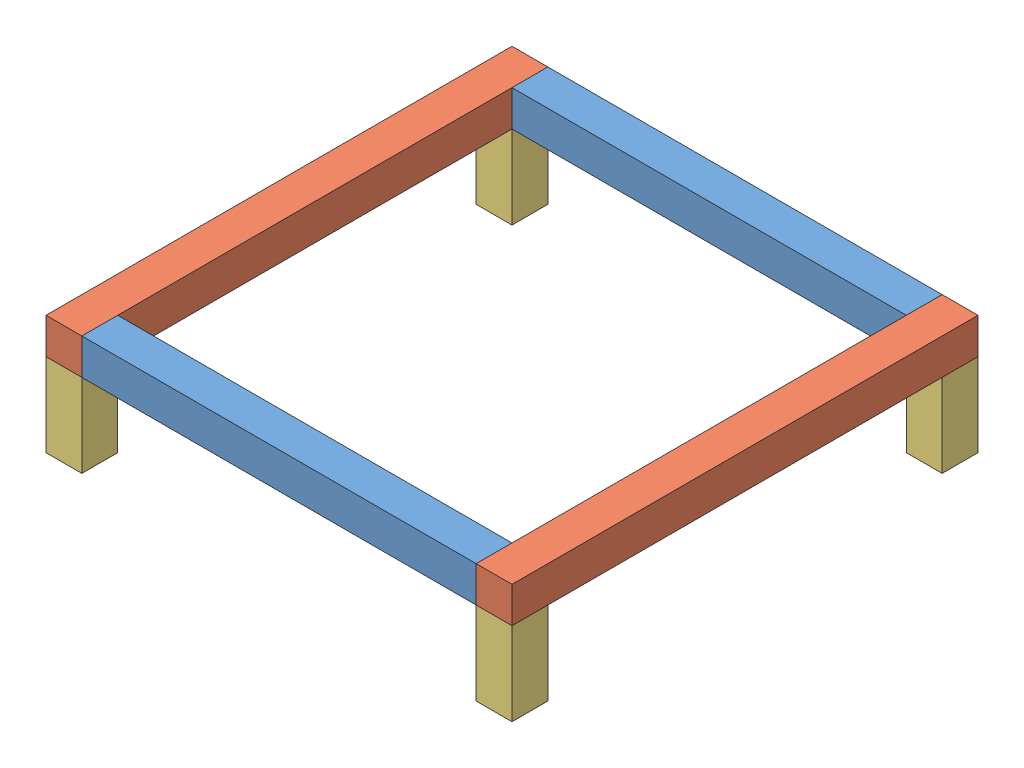
SolidWorks assembly MechanismHolder, configuration Default. Lengths in mm.
Overall size (330.2 84.33 330.2).
8 component instances, 3 part files, 21 mates.
Components (placement in the parent):
- 9.5in-1: 9.5in [Default] at (108.737 108.4161 187.2628) size (279.4 25.4 25.4)
- 11.5in-1: 11.5in [Default] at (261.137 108.4161 339.6628) x (0 0 1) z (-1 0 0) size (330.2 25.4 25.4)
- 9.5in-2: 9.5in [Default] at (108.737 108.4161 492.0628) size (279.4 25.4 25.4)
- 11.5in-2: 11.5in [Default] at (-43.663 108.4161 339.6628) x (0 0 -1) z (1 0 0) size (330.2 25.4 25.4)
- 2.32in-1: 2.32in [Default] at (-43.663 49.4881 492.0628) size (25.4 58.93 25.4)
- 2.32in-2: 2.32in [Default] at (-43.663 49.4881 187.2628) size (25.4 58.93 25.4)
- 2.32in-3: 2.32in [Default] at (261.137 49.4881 187.2628) size (25.4 58.93 25.4)
- 2.32in-4: 2.32in [Default] at (261.137 49.4881 492.0628) size (25.4 58.93 25.4)
Mates (geometry in assembly coordinates):
- Coincident1: coincident aligned: plane of 9.5in-2 through (108.737 133.8161 492.0628) normal (0 1 0); plane of 11.5in-2 through (-43.663 133.8161 339.6628) normal (0 1 0)
- Coincident2: coincident aligned: plane of 9.5in-1 through (108.737 133.8161 187.2628) normal (0 1 0); plane of 11.5in-2 through (-43.663 133.8161 339.6628) normal (0 1 0)
- Coincident3: coincident aligned: plane of 9.5in-1 through (108.737 133.8161 187.2628) normal (0 1 0); plane of 11.5in-1 through (261.137 133.8161 339.6628) normal (0 1 0)
- Coincident4: coincident anti-aligned: plane of 9.5in-2 through (-30.963 133.8161 504.7628) normal (-1 0 0); plane of 11.5in-2 through (-30.963 133.8161 504.7628) normal (1 0 0)
- Coincident5: coincident: plane of 9.5in-2 through (-30.963 133.8161 504.7628) normal (0 0 1); line of 11.5in-2 through (-56.363 133.8161 504.7628) axis (1 0 0)
- Coincident6: coincident anti-aligned: plane of 9.5in-1 through (-30.963 133.8161 199.9628) normal (-1 0 0); plane of 11.5in-2 through (-30.963 133.8161 504.7628) normal (1 0 0)
- Coincident7: coincident aligned: plane of 9.5in-1 through (-30.963 133.8161 174.5628) normal (0 0 -1); plane of 11.5in-2 through (-30.963 133.8161 174.5628) normal (0 0 -1)
- Coincident8: coincident aligned: plane of 9.5in-1 through (-30.963 133.8161 174.5628) normal (0 0 -1); plane of 11.5in-1 through (248.437 133.8161 174.5628) normal (0 0 -1)
- Coincident9: coincident anti-aligned: plane of 11.5in-1 through (248.437 133.8161 174.5628) normal (-1 0 0); plane of 9.5in-2 through (248.437 133.8161 504.7628) normal (1 0 0)
- Coincident10: coincident: plane of 9.5in-1 through (108.737 108.4161 187.2628) normal (0 -1 0); plane of 2.32in-2 through (-43.663 108.4161 200.1959) normal (0 1 0)
- Coincident11: coincident: plane of 9.5in-2 through (108.737 108.4161 492.0628) normal (0 -1 0); plane of 2.32in-3 through (235.737 142.1752 203.3999) normal (0 1 0)
- Coincident12: coincident: plane of 11.5in-1 through (261.137 108.4161 339.6628) normal (0 -1 0); plane of 2.32in-4 through (303.7852 108.4161 492.0628) normal (0 1 0)
- Coincident13: coincident: plane of 9.5in-2 through (-30.963 133.8161 504.7628) normal (0 0 1); plane of 2.32in-4 through (291.0852 108.4161 504.7628) normal (0 0 1)
- Coincident14: coincident aligned: plane of 11.5in-1 through (273.837 133.8161 174.5628) normal (1 0 0); plane of 2.32in-4 through (273.837 108.4161 504.7628) normal (1 0 0)
- Coincident15: coincident: plane of 11.5in-2 through (-43.663 108.4161 339.6628) normal (0 -1 0); plane of 2.32in-1 through (-43.663 108.4161 492.0628) normal (0 1 0)
- Coincident16: coincident: plane of 9.5in-2 through (-30.963 133.8161 504.7628) normal (0 0 1); plane of 2.32in-1 through (-56.363 108.4161 504.7628) normal (0 0 1)
- Coincident17: coincident aligned: plane of 11.5in-2 through (-56.363 133.8161 504.7628) normal (-1 0 0); plane of 2.32in-1 through (-56.363 108.4161 504.7628) normal (-1 0 0)
- Coincident18: coincident: plane of 11.5in-2 through (-56.363 133.8161 504.7628) normal (-1 0 0); plane of 2.32in-2 through (-56.363 108.4161 199.9628) normal (-1 0 0)
- Coincident19: coincident aligned: plane of 9.5in-1 through (-30.963 133.8161 174.5628) normal (0 0 -1); plane of 2.32in-2 through (-56.363 108.4161 174.5628) normal (0 0 -1)
- Coincident20: coincident: plane of 9.5in-1 through (-30.963 133.8161 174.5628) normal (0 0 -1); plane of 2.32in-3 through (248.437 108.4161 174.5628) normal (0 0 -1)
- Coincident21: coincident aligned: plane of 11.5in-1 through (273.837 133.8161 174.5628) normal (1 0 0); plane of 2.32in-3 through (273.837 108.4161 199.9628) normal (1 0 0)
